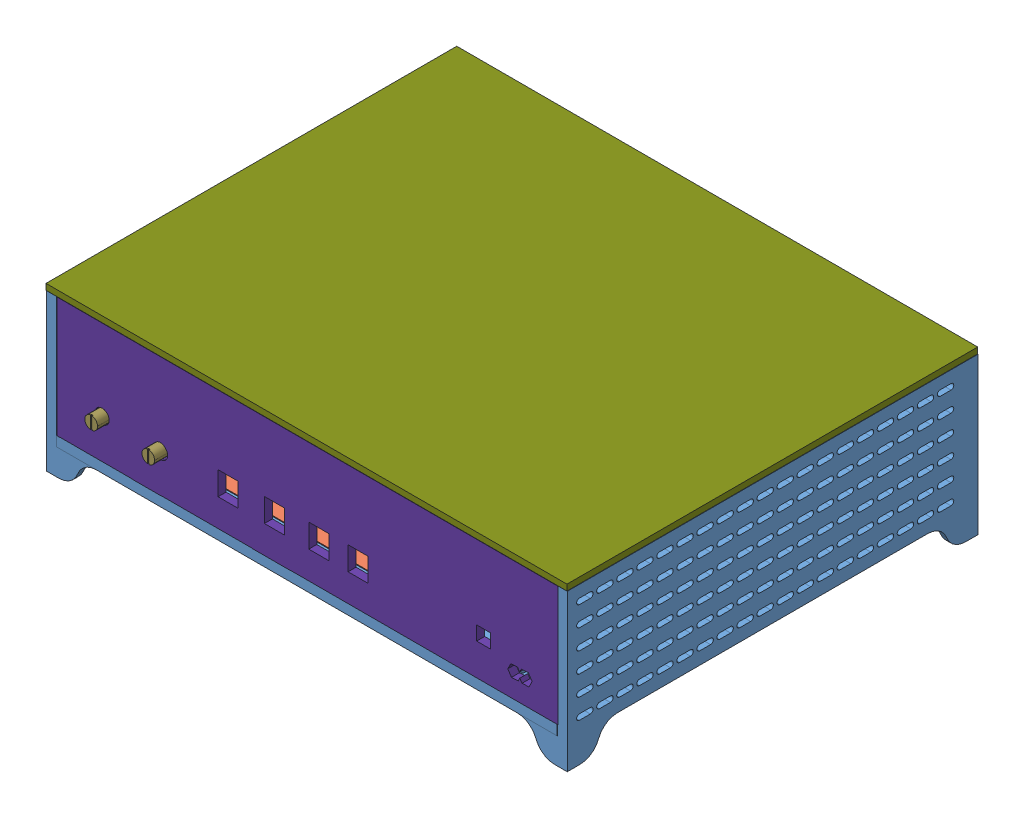
SolidWorks assembly Assem_funct, configuration Default. Lengths in mm.
Overall size (260.09 81.1 211).
276 component instances, 24 part files, 0 mates.
Components (placement in the parent):
- Bottom-1: Bottom [Default] at (122.2187 121.9823 223.4195) size (260 78 205)
- Main pcb.step-1: Main pcb.step [Default] at (7.8423 134.0807 355.0693) x (1 0 0) z (0 1 0) size (165 118.66 32.78)
  - Board.step-1: Board.step [Default] at origin size (165 100.5 0.41)
    - Open CASCADE STEP translator 6.8 2.1.1.step-1: Open CASCADE STEP translator 6.8 2.1.1.step [Default] at (0 0 -0.4115) size (165 100.5 0.41)
  - VR7.step-1: VR7.step [Default] at origin size (9.8 11.3 9.7)
    - User_Library-PNZ10ZA.step-1: User_Library-PNZ10ZA.step [Default] at (144.425 8.5751 1.0127) x (0 -1 0) z (0 0 -1) size (11.3 9.8 9.7)
  - R16.step-1: R16.step [Default] at origin size (2.54 13.26 5.59)
    - Resistor_0_25w.step-1: Resistor_0_25w.step [Default] at (138.5599 32.9401 0.254) x (0 1 0) z (1 0 0) size (13.26 5.59 2.54)
  - R15.step-1: R15.step [Default] at origin size (13.26 2.54 5.59)
    - Resistor_0_25w.step-1: Resistor_0_25w.step [Default] at (138.5001 22.0001 0.254) x (1 0 0) z (0 -1 0) size (13.26 5.59 2.54)
  - R14.step-1: R14.step [Default] at origin size (2.54 13.26 5.59)
    - Resistor_0_25w.step-1: Resistor_0_25w.step [Default] at (144.4999 56.5001 0.254) x (0 1 0) z (1 0 0) size (13.26 5.59 2.54)
  - J3.step-1: J3.step [Default] at origin size (5.76 19.91 10.41)
    - User_Library-B7B-XH-A.step-1: User_Library-B7B-XH-A.step [Default] at (161.5501 48.5499 0.0126) x (0 1 0) z (1 0 0) size (19.91 10.41 5.76)
  - C17.step-1: C17.step [Default] at origin size (8 8 14.5)
    - CAPACITOR_RADIAL_8X12.step-1: CAPACITOR_RADIAL_8X12.step [Default] at (150.8059 30.0245 0) x (-1 0 0) z (0 1 0) size (8 14.5 8)
  - C16.step-1: C16.step [Default] at origin size (8 8 14.5)
    - CAPACITOR_RADIAL_8X12.step-1: CAPACITOR_RADIAL_8X12.step [Default] at (150.8059 38.5245 0) x (-1 0 0) z (0 1 0) size (8 14.5 8)
  - C15.step-1: C15.step [Default] at origin size (8 8 14.5)
    - CAPACITOR_RADIAL_8X12.step-1: CAPACITOR_RADIAL_8X12.step [Default] at (150.8059 46.7789 0) x (-1 0 0) z (0 1 0) size (8 14.5 8)
  - C14.step-1: C14.step [Default] at origin size (8 8 14.5)
    - CAPACITOR_RADIAL_8X12.step-1: CAPACITOR_RADIAL_8X12.step [Default] at (150.8059 55.0332 0) x (-1 0 0) z (0 1 0) size (8 14.5 8)
  - C13.step-1: C13.step [Default] at origin size (8 8 14.5)
    - CAPACITOR_RADIAL_8X12.step-1: CAPACITOR_RADIAL_8X12.step [Default] at (150.8059 63.2875 0) x (-1 0 0) z (0 1 0) size (8 14.5 8)
  - C12.step-1: C12.step [Default] at origin size (8 8 14.5)
    - CAPACITOR_RADIAL_8X12.step-1: CAPACITOR_RADIAL_8X12.step [Default] at (150.8059 71.5418 0) x (-1 0 0) z (0 1 0) size (8 14.5 8)
  - U1.step-1: U1.step [Default] at origin size (19.7 7.89 6.68)
    - 6502308912.step-1: 6502308912.step [Default] at (92 40 0.51) size (19.7 6.6 4.57)
      - Extruded.step-1: Extruded.step [Default] at origin size (19.7 6.6 4.57)
    - 6502308752.step-1: 6502308752.step [Default] at (84.38 43.81 -1.6) size (0.72 0.27 1.6)
      - Extruded-0.step-1: Extruded-0.step [Default] at origin size (0.72 0.27 1.6)
    - 6502308592.step-1: 6502308592.step [Default] at (84.38 43.6225 2.66) size (1 0.64 0.27)
      - Extruded-1.step-1: Extruded-1.step [Default] at origin size (1 0.64 0.27)
    - 6502308432.step-1: 6502308432.step [Default] at (84.38 43.81 0) size (1 0.27 2.66)
      - Extruded-2.step-1: Extruded-2.step [Default] at origin size (1 0.27 2.66)
    - 6502308752.step-2: 6502308752.step [Default] at (86.92 43.81 -1.6) size (0.72 0.27 1.6)
      - Extruded-0.step-1: Extruded-0.step [Default] at origin size (0.72 0.27 1.6)
    - 6502308592.step-2: 6502308592.step [Default] at (86.92 43.6225 2.66) size (1 0.64 0.27)
      - Extruded-1.step-1: Extruded-1.step [Default] at origin size (1 0.64 0.27)
    - 6502308432.step-2: 6502308432.step [Default] at (86.92 43.81 0) size (1 0.27 2.66)
      - Extruded-2.step-1: Extruded-2.step [Default] at origin size (1 0.27 2.66)
    - 6502308752.step-3: 6502308752.step [Default] at (89.46 43.81 -1.6) size (0.72 0.27 1.6)
      - Extruded-0.step-1: Extruded-0.step [Default] at origin size (0.72 0.27 1.6)
    - 6502308592.step-3: 6502308592.step [Default] at (89.46 43.6225 2.66) size (1 0.64 0.27)
      - Extruded-1.step-1: Extruded-1.step [Default] at origin size (1 0.64 0.27)
    - 6502308432.step-3: 6502308432.step [Default] at (89.46 43.81 0) size (1 0.27 2.66)
      - Extruded-2.step-1: Extruded-2.step [Default] at origin size (1 0.27 2.66)
    - 6502308752.step-4: 6502308752.step [Default] at (92 43.81 -1.6) size (0.72 0.27 1.6)
      - Extruded-0.step-1: Extruded-0.step [Default] at origin size (0.72 0.27 1.6)
    - 6502308592.step-4: 6502308592.step [Default] at (92 43.6225 2.66) size (1 0.64 0.27)
      - Extruded-1.step-1: Extruded-1.step [Default] at origin size (1 0.64 0.27)
    - 6502308432.step-4: 6502308432.step [Default] at (92 43.81 0) size (1 0.27 2.66)
      - Extruded-2.step-1: Extruded-2.step [Default] at origin size (1 0.27 2.66)
    - 6502308752.step-5: 6502308752.step [Default] at (94.54 43.81 -1.6) size (0.72 0.27 1.6)
      - Extruded-0.step-1: Extruded-0.step [Default] at origin size (0.72 0.27 1.6)
    - 6502308592.step-5: 6502308592.step [Default] at (94.54 43.6225 2.66) size (1 0.64 0.27)
      - Extruded-1.step-1: Extruded-1.step [Default] at origin size (1 0.64 0.27)
    - 6502308432.step-5: 6502308432.step [Default] at (94.54 43.81 0) size (1 0.27 2.66)
      - Extruded-2.step-1: Extruded-2.step [Default] at origin size (1 0.27 2.66)
    - 6502308752.step-6: 6502308752.step [Default] at (97.08 43.81 -1.6) size (0.72 0.27 1.6)
      - Extruded-0.step-1: Extruded-0.step [Default] at origin size (0.72 0.27 1.6)
    - 6502308592.step-6: 6502308592.step [Default] at (97.08 43.6225 2.66) size (1 0.64 0.27)
      - Extruded-1.step-1: Extruded-1.step [Default] at origin size (1 0.64 0.27)
    - 6502308432.step-6: 6502308432.step [Default] at (97.08 43.81 0) size (1 0.27 2.66)
      - Extruded-2.step-1: Extruded-2.step [Default] at origin size (1 0.27 2.66)
    - 6502308752.step-7: 6502308752.step [Default] at (99.62 43.81 -1.6) size (0.72 0.27 1.6)
      - Extruded-0.step-1: Extruded-0.step [Default] at origin size (0.72 0.27 1.6)
    - 6502308592.step-7: 6502308592.step [Default] at (99.62 43.6225 2.66) size (1 0.64 0.27)
      - Extruded-1.step-1: Extruded-1.step [Default] at origin size (1 0.64 0.27)
    - 6502308432.step-7: 6502308432.step [Default] at (99.62 43.81 0) size (1 0.27 2.66)
      - Extruded-2.step-1: Extruded-2.step [Default] at origin size (1 0.27 2.66)
    - 6502308752.step-8: 6502308752.step [Default] at (99.62 36.19 -1.6) size (0.72 0.27 1.6)
      - Extruded-0.step-1: Extruded-0.step [Default] at origin size (0.72 0.27 1.6)
    - 6502308592.step-8: 6502308592.step [Default] at (99.62 36.3775 2.66) size (1 0.64 0.27)
      - Extruded-1.step-1: Extruded-1.step [Default] at origin size (1 0.64 0.27)
    - 6502308432.step-8: 6502308432.step [Default] at (99.62 36.19 0) size (1 0.27 2.66)
      - Extruded-2.step-1: Extruded-2.step [Default] at origin size (1 0.27 2.66)
    - 6502308752.step-9: 6502308752.step [Default] at (97.08 36.19 -1.6) size (0.72 0.27 1.6)
      - Extruded-0.step-1: Extruded-0.step [Default] at origin size (0.72 0.27 1.6)
    - 6502308592.step-9: 6502308592.step [Default] at (97.08 36.3775 2.66) size (1 0.64 0.27)
      - Extruded-1.step-1: Extruded-1.step [Default] at origin size (1 0.64 0.27)
    - 6502308432.step-9: 6502308432.step [Default] at (97.08 36.19 0) size (1 0.27 2.66)
      - Extruded-2.step-1: Extruded-2.step [Default] at origin size (1 0.27 2.66)
    - 6502308752.step-10: 6502308752.step [Default] at (94.54 36.19 -1.6) size (0.72 0.27 1.6)
      - Extruded-0.step-1: Extruded-0.step [Default] at origin size (0.72 0.27 1.6)
    - 6502308592.step-10: 6502308592.step [Default] at (94.54 36.3775 2.66) size (1 0.64 0.27)
      - Extruded-1.step-1: Extruded-1.step [Default] at origin size (1 0.64 0.27)
    - 6502308432.step-10: 6502308432.step [Default] at (94.54 36.19 0) size (1 0.27 2.66)
      - Extruded-2.step-1: Extruded-2.step [Default] at origin size (1 0.27 2.66)
    - 6502308752.step-11: 6502308752.step [Default] at (92 36.19 -1.6) size (0.72 0.27 1.6)
      - Extruded-0.step-1: Extruded-0.step [Default] at origin size (0.72 0.27 1.6)
    - 6502308592.step-11: 6502308592.step [Default] at (92 36.3775 2.66) size (1 0.64 0.27)
      - Extruded-1.step-1: Extruded-1.step [Default] at origin size (1 0.64 0.27)
    - 6502308432.step-11: 6502308432.step [Default] at (92 36.19 0) size (1 0.27 2.66)
      - Extruded-2.step-1: Extruded-2.step [Default] at origin size (1 0.27 2.66)
    - 6502308752.step-12: 6502308752.step [Default] at (89.46 36.19 -1.6) size (0.72 0.27 1.6)
      - Extruded-0.step-1: Extruded-0.step [Default] at origin size (0.72 0.27 1.6)
    - 6502308592.step-12: 6502308592.step [Default] at (89.46 36.3775 2.66) size (1 0.64 0.27)
      - Extruded-1.step-1: Extruded-1.step [Default] at origin size (1 0.64 0.27)
    - 6502308432.step-12: 6502308432.step [Default] at (89.46 36.19 0) size (1 0.27 2.66)
      - Extruded-2.step-1: Extruded-2.step [Default] at origin size (1 0.27 2.66)
    - 6502308752.step-13: 6502308752.step [Default] at (86.92 36.19 -1.6) size (0.72 0.27 1.6)
      - Extruded-0.step-1: Extruded-0.step [Default] at origin size (0.72 0.27 1.6)
    - 6502308592.step-13: 6502308592.step [Default] at (86.92 36.3775 2.66) size (1 0.64 0.27)
      - Extruded-1.step-1: Extruded-1.step [Default] at origin size (1 0.64 0.27)
    - 6502308432.step-13: 6502308432.step [Default] at (86.92 36.19 0) size (1 0.27 2.66)
      - Extruded-2.step-1: Extruded-2.step [Default] at origin size (1 0.27 2.66)
    - 6502308752.step-14: 6502308752.step [Default] at (84.38 36.19 -1.6) size (0.72 0.27 1.6)
      - Extruded-0.step-1: Extruded-0.step [Default] at origin size (0.72 0.27 1.6)
    - 6502308592.step-14: 6502308592.step [Default] at (84.38 36.3775 2.66) size (1 0.64 0.27)
      - Extruded-1.step-1: Extruded-1.step [Default] at origin size (1 0.64 0.27)
    - 6502308432.step-14: 6502308432.step [Default] at (84.38 36.19 0) size (1 0.27 2.66)
      - Extruded-2.step-1: Extruded-2.step [Default] at origin size (1 0.27 2.66)
  - R8.step-1: R8.step [Default] at origin size (2.54 13.26 5.59)
    - Resistor_0_25w.step-1: Resistor_0_25w.step [Default] at (112.4999 74.5001 0.254) x (0 1 0) z (1 0 0) size (13.26 5.59 2.54)
  - VR4.step-1: VR4.step [Default] at origin size (9.8 11.3 9.7)
    - User_Library-PNZ10ZA.step-1: User_Library-PNZ10ZA.step [Default] at (86.425 9.0751 1.0127) x (0 -1 0) z (0 0 -1) size (11.3 9.8 9.7)
  - C3.step-1: C3.step [Default] at origin size (27.84 16.65 28.51)
    - CAPACITOR_pol.step-1: CAPACITOR_pol.step [Default] at (27.4999 70.75 0.254) x (0 -1 0) z (-1 0 0) size (16.65 28.51 27.84)
  - VR6.step-1: VR6.step [Default] at origin size (9.8 11.3 9.7)
    - User_Library-PNZ10ZA.step-1: User_Library-PNZ10ZA.step [Default] at (127.4499 8.8751 1.0127) x (0 -1 0) z (0 0 -1) size (11.3 9.8 9.7)
  - VR5.step-1: VR5.step [Default] at origin size (21.03 39.81 32.43)
    - User_Library-POTENTIOMETER_BOURNS_3450S.step-1: User_Library-POTENTIOMETER_BOURNS_3450S.step [Default] at (48.9499 21.65 12.5076) x (-1 0 0) z (0 -1 0) size (21.03 32.43 39.81)
  - VR2.step-1: VR2.step [Default] at origin size (21.03 39.81 32.43)
    - User_Library-POTENTIOMETER_BOURNS_3450S.step-1: User_Library-POTENTIOMETER_BOURNS_3450S.step [Default] at (19.9499 22.1501 12.5076) x (-1 0 0) z (0 -1 0) size (21.03 32.43 39.81)
  - VR1.step-1: VR1.step [Default] at origin size (9.8 11.3 9.7)
    - User_Library-PNZ10ZA.step-1: User_Library-PNZ10ZA.step [Default] at (100.4249 9.5751 1.0127) x (0 -1 0) z (0 0 -1) size (11.3 9.8 9.7)
  - U2.step-1: U2.step [Default] at origin size (19.7 7.89 6.68)
    - 6502308432.step-1: 6502308432.step [Default] at (116.34 36.38 0) size (1 0.27 2.66)
      - Extruded-2.step-1: Extruded-2.step [Default] at origin size (1 0.27 2.66)
    - 6502308592.step-1: 6502308592.step [Default] at (116.34 36.5675 2.66) size (1 0.64 0.27)
      - Extruded-1.step-1: Extruded-1.step [Default] at origin size (1 0.64 0.27)
    - 6502308752.step-1: 6502308752.step [Default] at (116.34 36.38 -1.6) size (0.72 0.27 1.6)
      - Extruded-0.step-1: Extruded-0.step [Default] at origin size (0.72 0.27 1.6)
    - 6502308432.step-2: 6502308432.step [Default] at (118.88 36.38 0) size (1 0.27 2.66)
      - Extruded-2.step-1: Extruded-2.step [Default] at origin size (1 0.27 2.66)
    - 6502308592.step-2: 6502308592.step [Default] at (118.88 36.5675 2.66) size (1 0.64 0.27)
      - Extruded-1.step-1: Extruded-1.step [Default] at origin size (1 0.64 0.27)
    - 6502308752.step-2: 6502308752.step [Default] at (118.88 36.38 -1.6) size (0.72 0.27 1.6)
      - Extruded-0.step-1: Extruded-0.step [Default] at origin size (0.72 0.27 1.6)
    - 6502308432.step-3: 6502308432.step [Default] at (121.42 36.38 0) size (1 0.27 2.66)
      - Extruded-2.step-1: Extruded-2.step [Default] at origin size (1 0.27 2.66)
    - 6502308592.step-3: 6502308592.step [Default] at (121.42 36.5675 2.66) size (1 0.64 0.27)
      - Extruded-1.step-1: Extruded-1.step [Default] at origin size (1 0.64 0.27)
    - 6502308752.step-3: 6502308752.step [Default] at (121.42 36.38 -1.6) size (0.72 0.27 1.6)
      - Extruded-0.step-1: Extruded-0.step [Default] at origin size (0.72 0.27 1.6)
    - 6502308432.step-4: 6502308432.step [Default] at (123.96 36.38 0) size (1 0.27 2.66)
      - Extruded-2.step-1: Extruded-2.step [Default] at origin size (1 0.27 2.66)
    - 6502308592.step-4: 6502308592.step [Default] at (123.96 36.5675 2.66) size (1 0.64 0.27)
      - Extruded-1.step-1: Extruded-1.step [Default] at origin size (1 0.64 0.27)
    - 6502308752.step-4: 6502308752.step [Default] at (123.96 36.38 -1.6) size (0.72 0.27 1.6)
      - Extruded-0.step-1: Extruded-0.step [Default] at origin size (0.72 0.27 1.6)
    - 6502308432.step-5: 6502308432.step [Default] at (126.5 36.38 0) size (1 0.27 2.66)
      - Extruded-2.step-1: Extruded-2.step [Default] at origin size (1 0.27 2.66)
    - 6502308592.step-5: 6502308592.step [Default] at (126.5 36.5675 2.66) size (1 0.64 0.27)
      - Extruded-1.step-1: Extruded-1.step [Default] at origin size (1 0.64 0.27)
    - 6502308752.step-5: 6502308752.step [Default] at (126.5 36.38 -1.6) size (0.72 0.27 1.6)
      - Extruded-0.step-1: Extruded-0.step [Default] at origin size (0.72 0.27 1.6)
    - 6502308432.step-6: 6502308432.step [Default] at (129.04 36.38 0) size (1 0.27 2.66)
      - Extruded-2.step-1: Extruded-2.step [Default] at origin size (1 0.27 2.66)
    - 6502308592.step-6: 6502308592.step [Default] at (129.04 36.5675 2.66) size (1 0.64 0.27)
      - Extruded-1.step-1: Extruded-1.step [Default] at origin size (1 0.64 0.27)
    - 6502308752.step-6: 6502308752.step [Default] at (129.04 36.38 -1.6) size (0.72 0.27 1.6)
      - Extruded-0.step-1: Extruded-0.step [Default] at origin size (0.72 0.27 1.6)
    - 6502308432.step-7: 6502308432.step [Default] at (131.58 36.38 0) size (1 0.27 2.66)
      - Extruded-2.step-1: Extruded-2.step [Default] at origin size (1 0.27 2.66)
    - 6502308592.step-7: 6502308592.step [Default] at (131.58 36.5675 2.66) size (1 0.64 0.27)
      - Extruded-1.step-1: Extruded-1.step [Default] at origin size (1 0.64 0.27)
    - 6502308752.step-7: 6502308752.step [Default] at (131.58 36.38 -1.6) size (0.72 0.27 1.6)
      - Extruded-0.step-1: Extruded-0.step [Default] at origin size (0.72 0.27 1.6)
    - 6502308432.step-8: 6502308432.step [Default] at (131.58 44 0) size (1 0.27 2.66)
      - Extruded-2.step-1: Extruded-2.step [Default] at origin size (1 0.27 2.66)
    - 6502308592.step-8: 6502308592.step [Default] at (131.58 43.8125 2.66) size (1 0.64 0.27)
      - Extruded-1.step-1: Extruded-1.step [Default] at origin size (1 0.64 0.27)
    - 6502308752.step-8: 6502308752.step [Default] at (131.58 44 -1.6) size (0.72 0.27 1.6)
      - Extruded-0.step-1: Extruded-0.step [Default] at origin size (0.72 0.27 1.6)
    - 6502308432.step-9: 6502308432.step [Default] at (129.04 44 0) size (1 0.27 2.66)
      - Extruded-2.step-1: Extruded-2.step [Default] at origin size (1 0.27 2.66)
    - 6502308592.step-9: 6502308592.step [Default] at (129.04 43.8125 2.66) size (1 0.64 0.27)
      - Extruded-1.step-1: Extruded-1.step [Default] at origin size (1 0.64 0.27)
    - 6502308752.step-9: 6502308752.step [Default] at (129.04 44 -1.6) size (0.72 0.27 1.6)
      - Extruded-0.step-1: Extruded-0.step [Default] at origin size (0.72 0.27 1.6)
    - 6502308432.step-10: 6502308432.step [Default] at (126.5 44 0) size (1 0.27 2.66)
      - Extruded-2.step-1: Extruded-2.step [Default] at origin size (1 0.27 2.66)
    - 6502308592.step-10: 6502308592.step [Default] at (126.5 43.8125 2.66) size (1 0.64 0.27)
      - Extruded-1.step-1: Extruded-1.step [Default] at origin size (1 0.64 0.27)
    - 6502308752.step-10: 6502308752.step [Default] at (126.5 44 -1.6) size (0.72 0.27 1.6)
      - Extruded-0.step-1: Extruded-0.step [Default] at origin size (0.72 0.27 1.6)
    - 6502308432.step-11: 6502308432.step [Default] at (123.96 44 0) size (1 0.27 2.66)
      - Extruded-2.step-1: Extruded-2.step [Default] at origin size (1 0.27 2.66)
    - 6502308592.step-11: 6502308592.step [Default] at (123.96 43.8125 2.66) size (1 0.64 0.27)
      - Extruded-1.step-1: Extruded-1.step [Default] at origin size (1 0.64 0.27)
    - 6502308752.step-11: 6502308752.step [Default] at (123.96 44 -1.6) size (0.72 0.27 1.6)
      - Extruded-0.step-1: Extruded-0.step [Default] at origin size (0.72 0.27 1.6)
    - 6502308432.step-12: 6502308432.step [Default] at (121.42 44 0) size (1 0.27 2.66)
      - Extruded-2.step-1: Extruded-2.step [Default] at origin size (1 0.27 2.66)
    - 6502308592.step-12: 6502308592.step [Default] at (121.42 43.8125 2.66) size (1 0.64 0.27)
      - Extruded-1.step-1: Extruded-1.step [Default] at origin size (1 0.64 0.27)
    - 6502308752.step-12: 6502308752.step [Default] at (121.42 44 -1.6) size (0.72 0.27 1.6)
      - Extruded-0.step-1: Extruded-0.step [Default] at origin size (0.72 0.27 1.6)
    - 6502308432.step-13: 6502308432.step [Default] at (118.88 44 0) size (1 0.27 2.66)
      - Extruded-2.step-1: Extruded-2.step [Default] at origin size (1 0.27 2.66)
    - 6502308592.step-13: 6502308592.step [Default] at (118.88 43.8125 2.66) size (1 0.64 0.27)
      - Extruded-1.step-1: Extruded-1.step [Default] at origin size (1 0.64 0.27)
    - 6502308752.step-13: 6502308752.step [Default] at (118.88 44 -1.6) size (0.72 0.27 1.6)
      - Extruded-0.step-1: Extruded-0.step [Default] at origin size (0.72 0.27 1.6)
    - 6502308432.step-14: 6502308432.step [Default] at (116.34 44 0) size (1 0.27 2.66)
      - Extruded-2.step-1: Extruded-2.step [Default] at origin size (1 0.27 2.66)
    - 6502308592.step-14: 6502308592.step [Default] at (116.34 43.8125 2.66) size (1 0.64 0.27)
      - Extruded-1.step-1: Extruded-1.step [Default] at origin size (1 0.64 0.27)
    - 6502308752.step-14: 6502308752.step [Default] at (116.34 44 -1.6) size (0.72 0.27 1.6)
      - Extruded-0.step-1: Extruded-0.step [Default] at origin size (0.72 0.27 1.6)
    - 6502308912.step-1: 6502308912.step [Default] at (123.96 40.19 0.51) size (19.7 6.6 4.57)
      - Extruded.step-1: Extruded.step [Default] at origin size (19.7 6.6 4.57)
  - R13.step-1: R13.step [Default] at origin size (2.54 13.26 5.59)
    - Resistor_0_25w.step-1: Resistor_0_25w.step [Default] at (126.4999 74.5001 0.254) x (0 1 0) z (1 0 0) size (13.26 5.59 2.54)
  - R12.step-1: R12.step [Default] at origin size (13.26 2.54 5.59)
    - Resistor_0_25w.step-1: Resistor_0_25w.step [Default] at (44.4999 30.9999 0.254) x (-1 0 0) z (0 1 0) size (13.26 5.59 2.54)
  - R11.step-1: R11.step [Default] at origin size (13.26 2.54 5.59)
    - Resistor_0_25w.step-1: Resistor_0_25w.step [Default] at (61.4999 30.9999 0.254) x (-1 0 0) z (0 1 0) size (13.26 5.59 2.54)
  - R10.step-1: R10.step [Default] at origin size (2.54 13.26 5.59)
    - Resistor_0_25w.step-1: Resistor_0_25w.step [Default] at (70.9999 14.5001 0.254) x (0 1 0) z (1 0 0) size (13.26 5.59 2.54)
  - R9.step-1: R9.step [Default] at origin size (2.54 13.26 5.59)
    - Resistor_0_25w.step-1: Resistor_0_25w.step [Default] at (99.9999 74.5001 0.254) x (0 1 0) z (1 0 0) size (13.26 5.59 2.54)
  - R7.step-1: R7.step [Default] at origin size (2.54 13.26 5.59)
    - Resistor_0_25w.step-1: Resistor_0_25w.step [Default] at (117.0001 74.4999 0.254) x (0 -1 0) z (-1 0 0) size (13.26 5.59 2.54)
  - R6.step-1: R6.step [Default] at origin size (2.54 13.26 5.59)
    - Resistor_0_25w.step-1: Resistor_0_25w.step [Default] at (120.9999 74.5001 0.254) x (0 1 0) z (1 0 0) size (13.26 5.59 2.54)
  - R5.step-1: R5.step [Default] at origin size (2.54 13.26 5.59)
    - Resistor_0_25w.step-1: Resistor_0_25w.step [Default] at (103.9999 74.5001 0.254) x (0 1 0) z (1 0 0) size (13.26 5.59 2.54)
  - R4.step-1: R4.step [Default] at origin size (2.54 13.26 5.59)
    - Resistor_0_25w.step-1: Resistor_0_25w.step [Default] at (83.4999 74.0001 0.254) x (0 1 0) z (1 0 0) size (13.26 5.59 2.54)
  - R3.step-1: R3.step [Default] at origin size (2.54 13.26 5.59)
    - Resistor_0_25w.step-1: Resistor_0_25w.step [Default] at (93.5001 73.9999 0.254) x (0 -1 0) z (-1 0 0) size (13.26 5.59 2.54)
  - R2.step-1: R2.step [Default] at origin size (2.54 13.26 5.59)
    - Resistor_0_25w.step-1: Resistor_0_25w.step [Default] at (107.9999 74.5001 0.254) x (0 1 0) z (1 0 0) size (13.26 5.59 2.54)
  - R1.step-1: R1.step [Default] at origin size (2.54 13.26 5.59)
    - Resistor_0_25w.step-1: Resistor_0_25w.step [Default] at (88.0001 73.9999 0.254) x (0 -1 0) z (-1 0 0) size (13.26 5.59 2.54)
  - J2.step-1: J2.step [Default] at origin size (5.75 9.9 10.4)
    - User_Library-jst-b3b-xh-a.step-1: User_Library-jst-b3b-xh-a.step [Default] at (7.4501 46.5499 0.0128) x (0 1 0) z (1 0 0) size (9.9 10.4 5.75)
  - J1.step-1: J1.step [Default] at origin size (5.76 19.91 10.41)
    - User_Library-B7B-XH-A.step-1: User_Library-B7B-XH-A.step [Default] at (7.0501 71.0499 0.0126) x (0 1 0) z (1 0 0) size (19.91 10.41 5.76)
  - C11.step-1: C11.step [Default] at origin size (27.84 16.65 28.51)
    - CAPACITOR_pol.step-1: CAPACITOR_pol.step [Default] at (47.4999 65.0001 0.254) x (0 -1 0) z (-1 0 0) size (16.65 28.51 27.84)
  - C10.step-1: C10.step [Default] at origin size (27.84 16.65 28.51)
    - CAPACITOR_pol.step-1: CAPACITOR_pol.step [Default] at (27.9999 32.7501 0.254) x (0 -1 0) z (-1 0 0) size (16.65 28.51 27.84)
  - C8.step-1: C8.step [Default] at origin size (8 8 14.5)
    - CAPACITOR_RADIAL_8X12.step-1: CAPACITOR_RADIAL_8X12.step [Default] at (68.3001 54.5 0) x (1 0 0) z (0 -1 0) size (8 14.5 8)
  - C7.step-1: C7.step [Default] at origin size (8 8 14.5)
    - CAPACITOR_RADIAL_8X12.step-1: CAPACITOR_RADIAL_8X12.step [Default] at (68.3001 65.5001 0) x (1 0 0) z (0 -1 0) size (8 14.5 8)
  - C6.step-1: C6.step [Default] at origin size (8 8 14.5)
    - CAPACITOR_RADIAL_8X12.step-1: CAPACITOR_RADIAL_8X12.step [Default] at (68.3001 78.5 0) x (1 0 0) z (0 -1 0) size (8 14.5 8)
  - C5.step-1: C5.step [Default] at origin size (27.84 16.65 28.51)
    - CAPACITOR_pol.step-1: CAPACITOR_pol.step [Default] at (48.0001 43.4999 0.254) x (0 1 0) z (1 0 0) size (16.65 28.51 27.84)
  - C4.step-1: C4.step [Default] at origin size (27.84 16.65 28.51)
    - CAPACITOR_pol.step-1: CAPACITOR_pol.step [Default] at (27.9999 51.0001 0.254) x (0 -1 0) z (-1 0 0) size (16.65 28.51 27.84)
  - C2.step-1: C2.step [Default] at origin size (27.84 16.65 28.51)
    - CAPACITOR_pol.step-1: CAPACITOR_pol.step [Default] at (27.9999 90.5001 0.254) x (0 -1 0) z (-1 0 0) size (16.65 28.51 27.84)
  - C1.step-1: C1.step [Default] at origin size (16.65 27.84 28.51)
    - CAPACITOR_pol.step-1: CAPACITOR_pol.step [Default] at (48.0001 85.0001 0.254) x (-1 0 0) z (0 1 0) size (16.65 28.51 27.84)
- PCB_out.step-1: PCB_out.step [Default] at (120.9185 131.3509 282.9947) x (0 0 1) z (0 1 0) size (45.97 28.07 23.03)
- PCB1_powerSup.step-1: PCB1_powerSup.step [Default] at (171.6914 130.5657 97.8454) x (-1 0 0) z (0 1 0) size (46.23 26.67 24.4)
- top-1: top [Default] at (141.0859 187.0838 240.149) size (260 3 205)
- face-1: face [Default] at (117.5905 106.4354 363.2314) size (250 60 4)
- Transformador Chapas N°75.STEP-1: Transformador Chapas N°75.STEP [Default] at (210.3318 155.4348 226.5243) size (86 48.21 49.8)
  - CARRETE SECUNDARIO^Transformador Chapas N_75_Sin cables.STEP-1: CARRETE SECUNDARIO^Transformador Chapas N_75_Sin cables.STEP [Default] at (0 0.725 -14) x (0 0 -1) z (1 0 0) size (44.84 12.6 35.76)
    - Carrete Bobinado^CARRETE SECUNDARIO_Transformador Chapas N_75_Predeterminado.STEP-1: Carrete Bobinado^CARRETE SECUNDARIO_Transformador Chapas N_75_Predeterminado.STEP [Default] at origin size (44.84 12.6 35.76)
      - Bobinado^Carrete Bobinado_CARRETE SECUNDARIO_Transformador Chapas N_75_Predeterminado.STEP-1: Bobinado^Carrete Bobinado_CARRETE SECUNDARIO_Transformador Chapas N_75_Predeterminado.STEP [Default] at (0 1 0) x (1 0 0) z (0 1 0) size (43.78 33.63 11.06)
      - Cinta^Carrete Bobinado_CARRETE SECUNDARIO_Transformador Chapas N_75_Predeterminado.STEP-1: Cinta^Carrete Bobinado_CARRETE SECUNDARIO_Transformador Chapas N_75_Predeterminado.STEP [Default] at origin size (44.84 12.47 35.76)
  - CARRETE PRIMARIO^Transformador Chapas N_75_Sin cables.STEP-1: CARRETE PRIMARIO^Transformador Chapas N_75_Sin cables.STEP [Default] at (0 -0.3 -14.25) x (0 0 -1) z (-1 0 0) size (44.84 12.6 35.76)
    - Carrete Bobinado^CARRETE PRIMARIO_Transformador Chapas N_75_Predeterminado.STEP-1: Carrete Bobinado^CARRETE PRIMARIO_Transformador Chapas N_75_Predeterminado.STEP [Default] at origin size (44.84 12.6 35.76)
      - Bobinado^Carrete Bobinado_CARRETE PRIMARIO_Transformador Chapas N_75_Predeterminado.STEP-1: Bobinado^Carrete Bobinado_CARRETE PRIMARIO_Transformador Chapas N_75_Predeterminado.STEP [Default] at (0 1 0) x (1 0 0) z (0 1 0) size (43.78 33.63 11.06)
      - Cinta^Carrete Bobinado_CARRETE PRIMARIO_Transformador Chapas N_75_Predeterminado.STEP-1: Cinta^Carrete Bobinado_CARRETE PRIMARIO_Transformador Chapas N_75_Predeterminado.STEP [Default] at origin size (44.84 12.47 35.76)
  - Porta carrete^Transformador Chapas N_75_Predeterminado.STEP-1: Porta carrete^Transformador Chapas N_75_Predeterminado.STEP [Default] at (0 0 -14) x (0 0 -1) z (1 0 0) size (49.8 28 37.1)
  - CHAPA N75^Transformador Chapas N_75_Predeterminado.STEP-1: CHAPA N75^Transformador Chapas N_75_Predeterminado.STEP [Default] at origin size (57 47 28)
  - CHASIS^Transformador Chapas N_75_Predeterminado.STEP-1: CHASIS^Transformador Chapas N_75_Predeterminado.STEP [Default] at origin size (86 48.21 29.42)
